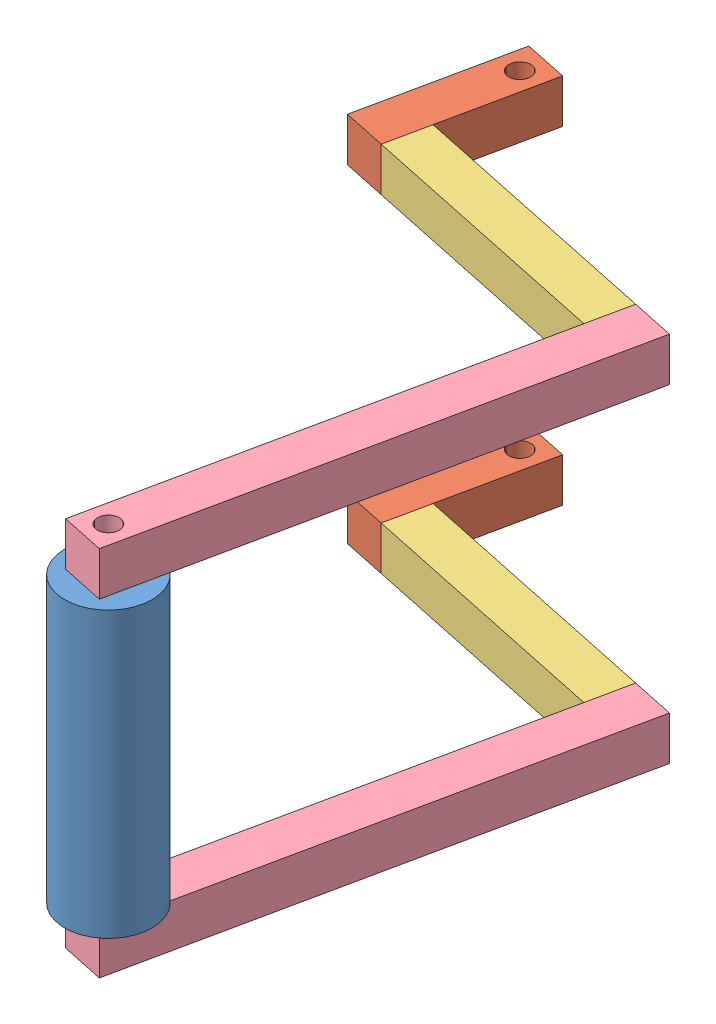
SolidWorks assembly scoring mech v1, configuration Default. Lengths in mm.
Overall size (204.07 215.9 398.25).
7 component instances, 4 part files, 15 mates.
Components (placement in the parent):
- intake rollers-2: intake rollers [Default] at (294.5874 283.4141 486.6007) x (0.660065 0 -0.751209) z (0.751209 0 0.660065) size (50.8 165.1 50.8)
- roller holder-2: roller holder [Default] at (185.8135 258.0141 202.2775) x (0.206339 0 -0.978481) z (0.978481 0 0.206339) size (88.9 25.4 25.4)
- roller part 1-1: roller part 1 [Default] at (188.0707 258.0141 191.5735) x (0.978481 0 0.206339) z (-0.206339 0 0.978481) size (152.4 25.4 25.4)
- roller part 1-4: roller part 1 [Default] at (188.0707 448.5141 191.5735) x (0.978481 0 0.206339) z (-0.206339 0 0.978481) size (152.4 25.4 25.4)
- roller holder-5: roller holder [Default] at (185.8135 448.5141 202.2775) x (0.206339 0 -0.978481) z (0.978481 0 0.206339) size (88.9 25.4 25.4)
- roller part 2 holes-2: roller part 2 holes [Default] at (362.0446 448.5141 228.2605) x (0.978481 0 0.206339) z (-0.206339 0 0.978481) size (25.4 25.4 279.4)
- roller part 2 holes-4: roller part 2 holes [Default] at (362.0446 258.0141 228.2605) x (0.978481 0 0.206339) z (-0.206339 0 0.978481) size (25.4 25.4 279.4)
Mates (geometry in assembly coordinates):
- Coincident28: coincident aligned: plane of roller holder-2 through (185.8135 283.4141 202.2775) normal (0 1 0); plane of roller part 1-1 through (337.1912 283.4141 223.0195) normal (0 1 0)
- Coincident29: coincident anti-aligned: plane of roller holder-2 through (182.8297 283.4141 216.4269) normal (0.978481 0 0.206339); plane of roller part 1-1 through (188.0707 258.0141 191.5735) normal (-0.978481 0 -0.206339)
- Coincident30: coincident aligned: plane of roller holder-2 through (182.8297 283.4141 216.4269) normal (-0.206339 0 0.978481); plane of roller part 1-1 through (331.9502 258.0141 247.8729) normal (-0.206339 0 0.978481)
- Coincident55: coincident aligned: plane of roller part 1-4 through (337.1912 473.9141 223.0195) normal (0 1 0); plane of roller holder-5 through (185.8135 473.9141 202.2775) normal (0 1 0)
- Coincident56: coincident anti-aligned: plane of roller part 1-4 through (188.0707 448.5141 191.5735) normal (-0.978481 0 -0.206339); plane of roller holder-5 through (182.8297 473.9141 216.4269) normal (0.978481 0 0.206339)
- Coincident60: coincident aligned: plane of roller part 1-4 through (331.9502 448.5141 247.8729) normal (-0.206339 0 0.978481); plane of roller holder-5 through (182.8297 473.9141 216.4269) normal (-0.206339 0 0.978481)
- Coincident69: coincident anti-aligned: plane of roller part 1-4 through (337.1912 448.5141 223.0195) normal (0.978481 0 0.206339); plane of roller part 2 holes-2 through (279.5402 448.5141 496.407) normal (-0.978481 0 -0.206339)
- Coincident70: coincident aligned: plane of roller part 1-4 through (337.1912 473.9141 223.0195) normal (0 1 0); plane of roller part 2 holes-2 through (304.3936 473.9141 501.6479) normal (0 1 0)
- Coincident71: coincident aligned: plane of roller part 1-4 through (337.1912 448.5141 223.0195) normal (0.206339 0 -0.978481); plane of roller part 2 holes-2 through (362.0446 448.5141 228.2605) normal (0.206339 0 -0.978481)
- Coincident72: coincident aligned: circle of intake rollers-2; circle of roller part 2 holes-2
- Coincident77: coincident anti-aligned: plane of roller part 1-1 through (337.1912 258.0141 223.0195) normal (0.978481 0 0.206339); plane of roller part 2 holes-4 through (279.5402 258.0141 496.407) normal (-0.978481 0 -0.206339)
- Coincident78: coincident aligned: plane of roller part 1-1 through (337.1912 258.0141 223.0195) normal (0.206339 0 -0.978481); plane of roller part 2 holes-4 through (362.0446 258.0141 228.2605) normal (0.206339 0 -0.978481)
- Coincident79: coincident aligned: plane of roller part 1-1 through (337.1912 283.4141 223.0195) normal (0 1 0); plane of roller part 2 holes-4 through (304.3936 283.4141 501.6479) normal (0 1 0)
- Coincident81: coincident aligned: circle of intake rollers-2; circle of roller part 2 holes-4
- Concentric4: concentric aligned: cylinder of roller holder-2 through (186.126 283.4141 139.2461) axis (0 -1 0) radius 6.35; cylinder of roller holder-5 through (186.126 473.9141 139.2461) axis (0 -1 0) radius 6.35
